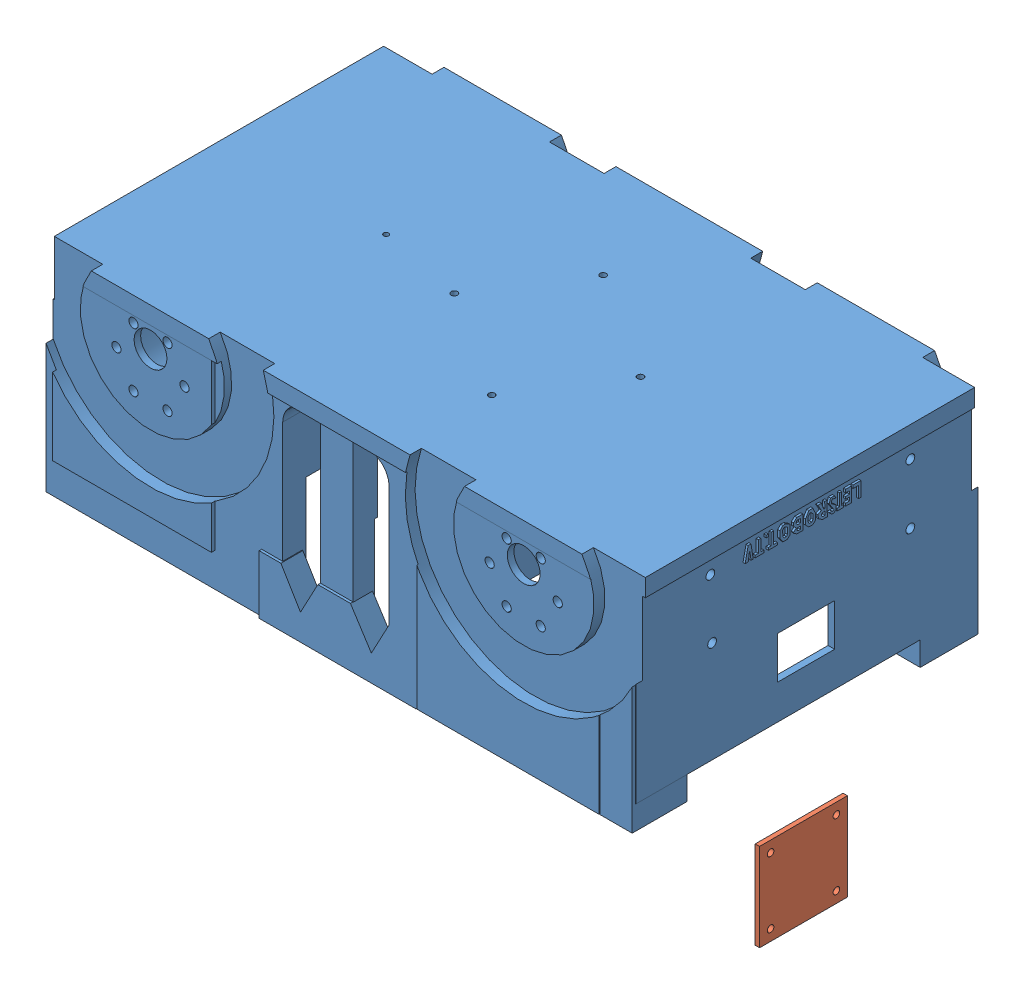
SolidWorks assembly ChassisLidPiCover, configuration Default. Lengths in mm.
Overall size (295.52 182.65 194.12).
8 component instances, 7 part files, 14 mates.
Components (placement in the parent):
- Chassis3ForSaleRelabeled-1: Chassis3ForSaleRelabeled [Default] at (42.9296 190.2821 237.8976) size (295.52 106.02 194.12)
- Part1^ChassisLidPiCover-1: Part1^ChassisLidPiCover [Default] at origin (virtual)
- Lid-1: Lid [Default] at (-12.9622 111.2528 322.8356) size (269.21 44 166) (hidden)
- Part2^ChassisLidPiCover-1: Part2^ChassisLidPiCover [Default] at origin (virtual)
- RaspberryPi3-1: RaspberryPi3 [Default] at (200.6457 109.1528 247.2463) x (-1 0 0) z (0 -1 0) size (89.64 57.31 18.92) (hidden)
- PiCover-1: PiCover [Default] at (259.9106 71.2528 310.8356) x (0 0 -1) z (1 0 0) size (139.99 42 97.39) (hidden)
- PiCover-2: PiCover [Default] at (259.9302 71.2528 310.8515) x (0 0 -1) z (1 0 0) size (139.99 42 97.39) (hidden)
- ELP170DegreeCamera-1: ELP170DegreeCamera [Default] at (256.9877 78.4432 256.5136) x (0 -1 0) z (0 0 1) size (40 2 40)
Mates (geometry in assembly coordinates):
- Distance2: distance = 0.2 mm anti-aligned: plane of Lid-1 through (-9.9622 115.2528 159.835) normal (0 0 1); plane of Chassis3ForSaleRelabeled-1 through (231.3169 214.4528 160.035) normal (0 0 -1)
- Distance3: distance = 0.2 mm anti-aligned: plane of Chassis3ForSaleRelabeled-1 through (42.9296 115.4528 237.8976) normal (0 -1 0); plane of Lid-1 through (-12.9622 115.2528 322.8356) normal (0 1 0)
- Coincident1: coincident anti-aligned: plane of Lid-1 through (-12.9622 111.2528 322.8356) normal (0 -1 0); plane of RaspberryPi3-1 through (241.3615 111.2528 219.3938) normal (0 1 0)
- Distance6: distance = 16 mm aligned: plane of RaspberryPi3-1 through (249.0877 109.9128 219.8256) normal (1 0 0); plane of Lid-1 through (265.0877 135.2528 322.8356) normal (1 0 0)
- Distance7: distance = 50 mm aligned: plane of RaspberryPi3-1 through (246.0977 109.9128 272.8356) normal (0 0 1); plane of Lid-1 through (-12.9622 135.2528 322.8356) normal (0 0 1)
- PiCoverToFront: distance = 0 mm aligned: plane of PiCover-1 through (162.5172 69.2528 310.8356) normal (-1 0 0); plane of Lid-1 through (162.5172 135.2528 166.1952) normal (-1 0 0)
- Distance9: distance = 12 mm aligned: plane of Lid-1 through (-12.9622 135.2528 322.8356) normal (0 0 1); plane of PiCover-1 through (259.9106 69.2528 310.8356) normal (0 0 1)
- Coincident11: coincident anti-aligned: plane of Lid-1 through (-12.9622 111.2528 322.8356) normal (0 -1 0); plane of PiCover-1 through (259.9106 111.2528 310.8356) normal (0 1 0)
- Distance11: distance = 0.1 mm anti-aligned: plane of Chassis3ForSaleRelabeled-1 through (261.9877 214.4528 160.035) normal (1 0 0); plane of Lid-1 through (262.0877 115.2528 159.835) normal (-1 0 0)
- Concentric2: concentric anti-aligned: cylinder of Lid-1 through (210.0516 123.031 181.227) axis (0 -1 0) radius 2.75; cylinder of PiCover-2 through (210.0516 69.2528 181.227) axis (0 1 0) radius 2.75
- Coincident12: coincident anti-aligned: plane of Lid-1 through (-12.9622 111.2528 322.8356) normal (0 -1 0); plane of PiCover-2 through (259.9302 111.2528 310.8515) normal (0 1 0)
- Parallel1: parallel aligned: plane of Lid-1 through (265.0877 135.2528 322.8356) normal (1 0 0); plane of PiCover-2 through (259.9302 69.2528 310.8515) normal (1 0 0)
- Coincident13: coincident anti-aligned: plane of Chassis3ForSaleRelabeled-1 through (258.9877 190.2821 237.8976) normal (-1 0 0); plane of ELP170DegreeCamera-1 through (258.9877 78.4432 256.5136) normal (1 0 0)
- Parallel2: parallel aligned: plane of Chassis3ForSaleRelabeled-1 through (258.9877 190.2821 237.8976) normal (-1 0 0); plane of ELP170DegreeCamera-1 through (256.9877 78.4432 256.5136) normal (-1 0 0)
